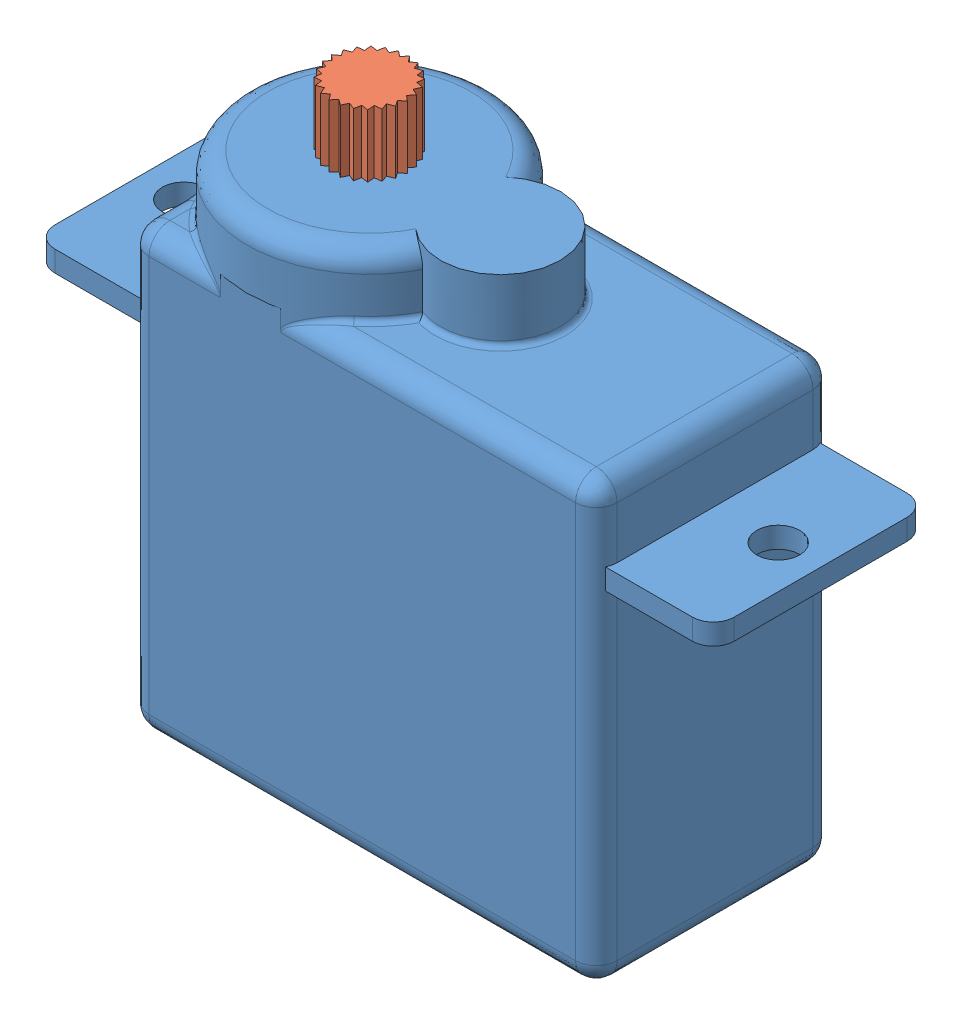
SolidWorks assembly HS-55 Servo, configuration Default. Lengths in mm.
Overall size (32.54 27 11.73).
2 component instances, 2 part files, 3 mates.
Components (placement in the parent):
- Hi-Tec HS-55 Body-1: Hi-Tec HS-55 Body [Default] at origin size (32.54 24.06 11.73)
- Hi-Tec HS-55 Shaft-1: Hi-Tec HS-55 Shaft [Default] at (0 3 0) x (0.999553 0 0.029907) z (-0.029907 0 0.999553) size (3.75 3 3.75)
Mates (geometry in assembly coordinates):
- Coincident1: coordinate: point of Hi-Tec HS-55 Body-1; point of assembly
- Coincident2: coincident anti-aligned: plane of Hi-Tec HS-55 Body-1 through (3.1369 0 0) normal (0 1 0); plane of Hi-Tec HS-55 Shaft-1 through (0 0 0) normal (0 -1 0)
- Coincident4: coincident anti-aligned: line of Hi-Tec HS-55 Shaft-1 through (0 3.15 0) axis (0 -1 0); line of assembly
